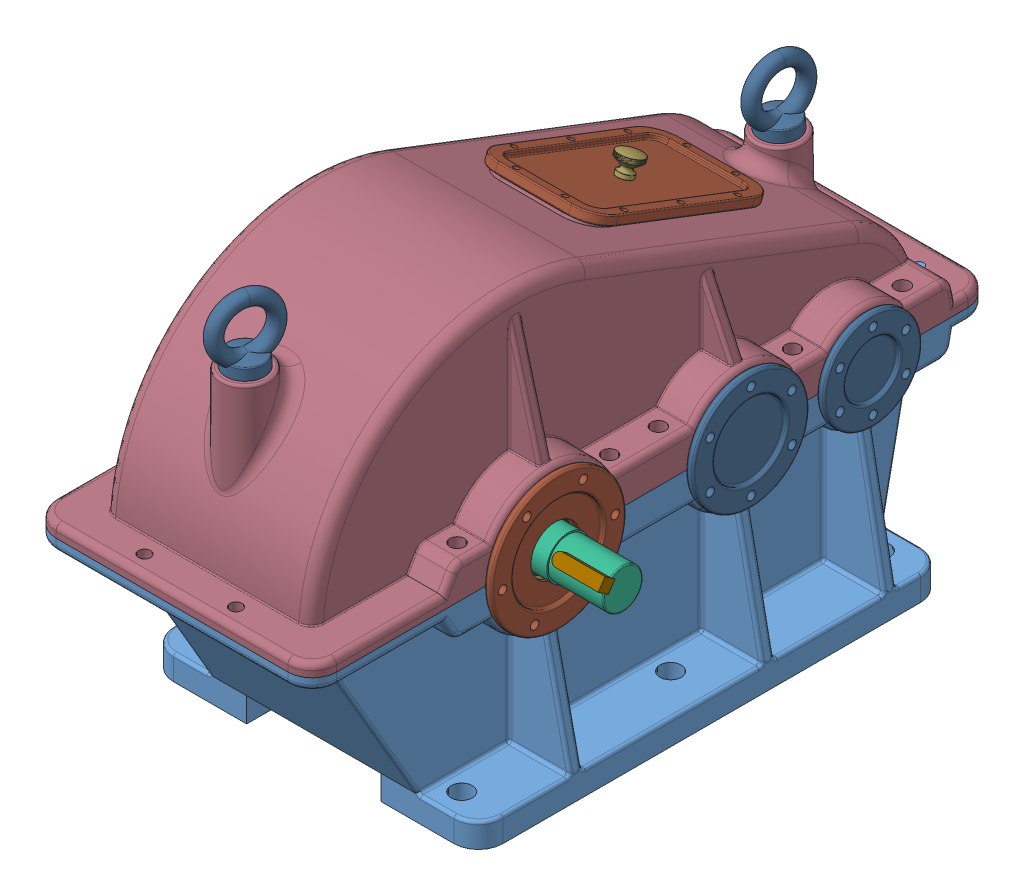
SolidWorks assembly Helical Gearbox Assembly, configuration Default. Lengths in mm.
Overall size (677.13 747.69 1115).
43 component instances, 31 part files, 90 mates.
Components (placement in the parent):
- 01. Shell-1: 01. Shell [Default] at (272.181 704.8513 957.0031) size (540.65 360 1115)
- Oil Plug Seal^Helical Gearbox Assembly-1: Oil Plug Seal^Helical Gearbox Assembly [Default] at (272.181 704.8513 487.0031) x (-1 0 0) z (0 0 -1) size (40 40 3) (virtual)
- 14. Oil Probe-1: 14. Oil Probe [Default] at (272.181 440.499 572.0097) x (-1 0 0) z (0 -0.660132 -0.75115) size (24 180 24)
- 15. Oil Removal Nut-1: 15. Oil Removal Nut [Default] at (272.181 424.8513 484.0031) x (1 0 0) z (0 1 0) size (30 28.09 30)
- 04. Gear 84-1: 04. Gear 84 [ISO - Spur gear 6M 84T 20PA 125FW ---S84A75H50L90.0N] at (159.681 704.8513 1122.0031) x (1 0 0) z (0 -0.823359 0.567521) size (125 515.77 515.77)
- 06. Shaft Slow-1: 06. Shaft Slow [Default] at (83.181 704.8513 1122.0031) x (0 -0.823359 0.567521) z (-1 0 0) size (110 110 536.13)
- 10. Ring Distance 85x137.5-1: 10. Ring Distance 85x137.5 [Default] at (284.681 704.8513 1122.0031) x (-1 0 0) z (0 -0.99103 -0.133637) size (137.5 110 110)
- 11.3 Key 115x16 D18-1: 11.3 Key 115x16 D18 [Default] at (222.181 725.8496 1152.4674) x (1 0 0) z (0 -0.823359 0.567521) size (115 16 18)
- 11.4 Key 160x20 D20-1: 11.4 Key 160x20 D20 [Default] at (619.181 717.6205 1140.5287) x (1 0 0) z (0 -0.823359 0.567521) size (80 20 20)
- 16. Cover Plate Bearing-1: 16. Cover Plate Bearing [CV-80] at (36.181 704.8513 1122.0031) size (55 220 220)
- 17. Cover Plate Bearing (Hole)-1: 17. Cover Plate Bearing (Hole) [CV-80] at (508.181 704.8513 1122.0031) x (-1 0 0) z (0 -0.429637 -0.903002) size (55 220 220)
- 19. Cuff 70x92-1: 19. Cuff 70x92 [Default] at (502.181 704.8513 1122.0031) size (10 92 92)
  - Part2^19. Cuff 70x92-1: Part2^19. Cuff 70x92 [Default] at origin size (10 92 92) (virtual)
  - Part3^19. Cuff 70x92-1: Part3^19. Cuff 70x92 [Default] at origin size (6.5 91 91) (virtual)
  - Part4^19. Cuff 70x92-1: Part4^19. Cuff 70x92 [Default] at origin size (3.73 83.55 83.54) (virtual)
- angular contact ball bearing_68_iso-1: angular contact ball bearing_68_iso [ISO 15 ABB - 0375 - 12,SI,NC,12_68] at (440.681 704.8513 1122.0031) x (-1 0 0) z (0 -0.924225 -0.381849) size (37 160 160)
- angular contact ball bearing_68_iso-2: angular contact ball bearing_68_iso [ISO 15 ABB - 0375 - 12,SI,NC,12_68] at (103.681 704.8513 1122.0031) size (37 160 160)
- 05. Shaft Speed Gear 28-1: 05. Shaft Speed Gear 28 [ISO - Spur gear 4M 28T 20PA 85FW ---S28A75H50L0.8N] at (398.681 704.8513 607.0031) x (-1 0 0) z (0 -0.40996 -0.912103) size (507 119.49 119.49)
- 11.5 Key 100x12 D12-1: 11.5 Key 100x12 D12 [Default] at (-57.819 715.3405 602.2886) x (-1 0 0) z (0 -0.40996 -0.912103) size (50 12 12)
- 16. Cover Plate Bearing-2: 16. Cover Plate Bearing [CV-55] at (508.181 704.8513 607.0031) x (-1 0 0) z (0 -0.866025 -0.5) size (67 160 160)
- 17. Cover Plate Bearing (Hole)-2: 17. Cover Plate Bearing (Hole) [CV-55] at (36.181 704.8513 607.0031) x (1 0 0) z (0 0.866025 0.5) size (67 160 160)
- 18. Cuff 40x60-1: 18. Cuff 40x60 [Default] at (42.181 704.8513 607.0031) x (-1 0 0) z (0 0 -1) size (10 60 60)
  - Part1^18. Cuff 40x60-1: Part1^18. Cuff 40x60 [Default] at origin size (6.5 59 59) (virtual)
  - Part2^18. Cuff 40x60-1: Part2^18. Cuff 40x60 [Default] at origin size (10 60 60) (virtual)
  - Part3^18. Cuff 40x60-1: Part3^18. Cuff 40x60 [Default] at origin size (3.75 53.63 53.66) (virtual)
- angular contact ball bearing_68_iso-3: angular contact ball bearing_68_iso [ISO 15 ABB - 0345 - 10,SI,NC,10_68] at (434.681 704.8513 607.0031) x (-1 0 0) z (0 -0.924225 -0.381849) size (25 100 100)
- angular contact ball bearing_68_iso-4: angular contact ball bearing_68_iso [ISO 15 ABB - 0345 - 10,SI,NC,10_68] at (109.681 704.8513 607.0031) x (-1 0 0) z (0 -0.924225 -0.381849) size (25 100 100)
- 03. Gear 72-1: 03. Gear 72 [ISO - Spur gear 4M 72T 20PA 80FW ---S72A75H50L80.0N] at (316.681 704.8513 807.0031) x (1 0 0) z (0 0.837056 -0.547117) size (80 295.82 295.82)
- 07. Shaft Middle-1: 07. Shaft Middle [Default] at (455.181 704.8513 807.0031) x (0 0.837056 -0.547117) z (-1 0 0) size (100 100 365.5)
- 08. Ring Distance 60x25.5-1: 08. Ring Distance 60x25.5 [Default] at (396.681 704.8513 807.0031) x (0 -0.984693 -0.174299) z (1 0 0) size (90 90 25.5)
- 09. Ring Distance 60x35-1: 09. Ring Distance 60x35 [Default] at (157.681 704.8513 807.0031) x (1 0 0) z (0 0.963027 -0.269404) size (35 90 90)
- 11.1 Key 70x12 D16-1: 11.1 Key 70x12 D16 [Default] at (356.681 686.2494 778.5432) x (1 0 0) z (0 0.837056 -0.547117) size (70 12 16)
- 16. Cover Plate Bearing-3: 16. Cover Plate Bearing [CV-65] at (36.181 704.8513 807.0031) size (61 190 190)
- angular contact ball bearing_68_iso-5: angular contact ball bearing_68_iso [ISO 15 ABB - 0360 - 10,SI,NC,10_68] at (437.681 704.8513 807.0031) x (-1 0 0) z (0 -0.924225 -0.381849) size (31 130 130)
- angular contact ball bearing_68_iso-6: angular contact ball bearing_68_iso [ISO 15 ABB - 0360 - 10,SI,NC,10_68] at (106.681 704.8513 807.0031) x (-1 0 0) z (0 -0.924225 -0.381849) size (31 130 130)
- 11.2 Key 125x12 D12-1: 11.2 Key 125x12 D12 [Default] at (222.681 690.3527 784.8211) x (1 0 0) z (0 0.837056 -0.547117) size (125 12 12)
- 16. Cover Plate Bearing-4: 16. Cover Plate Bearing [CV-65] at (508.181 704.8513 807.0031) x (-1 0 0) z (0 -0.866025 -0.5) size (61 190 190)
- Gear 21-2: Gear 21 [ISO - Spur gear 6M 21T 20PA 130FW ---S21A75H50L65.0N] at (157.681 704.8513 807.0031) x (1 0 0) z (0 0.647031 -0.762463) size (130 137.45 137.82)
- 02. Eye Bolt-1: 02. Eye Bolt [Default] at (272.181 984.8513 1394.5031) x (0.963727 0 0.266888) z (-0.266888 0 0.963727) size (63 164 109.27)
- 12.Door Cover Plate-1: 12.Door Cover Plate [Default] at (272.181 935.8311 775.5954) x (1 0 0) z (0 0.359223 0.933252) size (200 25.72 320)
- 13. Blunking Plug-1: 13. Blunking Plug [Default] at (272.181 927.8985 778.6488) x (-0.612037 -0.284084 -0.738043) z (0.790829 -0.219858 -0.571185) size (40.1 50 40.08)
- 20. Cover-1: 20. Cover [Default] at (272.181 704.8513 957.0031) size (462.08 335 1115)
- 02. Eye Bolt-2: 02. Eye Bolt [Default] at (272.181 884.8513 519.5031) x (0.996756 0 0.080487) z (-0.080487 0 0.996756) size (63 164 109.27)
Mates (geometry in assembly coordinates):
- Concentric1: concentric: cylinder of 01. Shell-1 through (42.181 704.8513 1122.0031) axis (1 0 0) radius 80; cylinder of 17. Cover Plate Bearing (Hole)-1 through (502.181 704.8513 1122.0031) axis (-1 0 0) radius 80
- Coincident1: coincident: plane of 01. Shell-1 through (502.181 684.8513 957.0031) normal (1 0 0); plane of 17. Cover Plate Bearing (Hole)-1 through (502.181 804.1815 1074.7431) normal (-1 0 0)
- Concentric2: concentric: cylinder of 01. Shell-1 through (502.181 704.8513 1122.0031) axis (-1 0 0) radius 80; cylinder of 16. Cover Plate Bearing-1 through (42.181 704.8513 1122.0031) axis (1 0 0) radius 80
- Coincident2: coincident: plane of 01. Shell-1 through (42.181 684.8513 957.0031) normal (-1 0 0); plane of 16. Cover Plate Bearing-1 through (42.181 814.8513 1122.0031) normal (1 0 0)
- Concentric3: concentric: cylinder of assembly; cylinder of assembly; cylinder of 01. Shell-1 through (502.181 704.8513 1122.0031) axis (-1 0 0) radius 80; cylinder of 06. Shaft Slow-1 through (83.181 704.8513 1122.0031) axis (-1 0 0) radius 42.5; plane of ?; plane of ?
- Coincident3: coincident: line of assembly; plane of assembly; line of 06. Shaft Slow-1 through (549.181 714.1673 1153.1393) axis (1 0 0); plane of ?; plane of ?; plane of 11.4 Key 160x20 D20-1 through (549.181 720.7374 1162.6711) normal (0 -0.823359 0.567521)
- Coincident4: coincident: plane of 06. Shaft Slow-1 through (619.181 717.6205 1140.5287) normal (0 0.567521 0.823359); line of 11.4 Key 160x20 D20-1 through (619.181 725.8541 1134.8535) axis (0 -0.823359 0.567521)
- Coincident5: coincident: circle of 06. Shaft Slow-1; circle of 11.4 Key 160x20 D20-1
- Concentric4: concentric: cylinder of assembly; cylinder of assembly; cylinder of 06. Shaft Slow-1 through (270.681 731.5248 1160.701) axis (0 -0.567521 -0.823359) radius 9; plane of ?; plane of ?; cylinder of 11.3 Key 115x16 D18-1 through (270.681 734.9299 1165.6412) axis (0 -0.567521 -0.823359) radius 9
- Coincident6: coincident: line of 06. Shaft Slow-1 through (173.681 722.4635 1163.4134) axis (1 0 0); plane of 11.3 Key 115x16 D18-1 through (173.681 727.5197 1170.7489) normal (0 -0.823359 0.567521)
- Coincident7: coincident: plane of 06. Shaft Slow-1 through (270.681 725.8496 1152.4674) normal (0 0.567521 0.823359); line of 11.3 Key 115x16 D18-1 through (173.681 718.4394 1157.5751) axis (1 0 0)
- Concentric5: concentric: cylinder of assembly; cylinder of assembly; cylinder of 06. Shaft Slow-1 through (83.181 704.8513 1122.0031) axis (-1 0 0) radius 42.5; plane of ?; plane of ?; plane of ?; cylinder of 10. Ring Distance 85x137.5-1 through (379.571 704.8513 1122.0031) axis (1 0 0) radius 42.5
- Concentric6: concentric: cylinder of assembly; cylinder of assembly; cylinder of 04. Gear 84-1 through (284.6811 704.8513 1122.0031) axis (-1 0 0) radius 45; cylinder of 06. Shaft Slow-1 through (83.181 704.8513 1122.0031) axis (-1 0 0) radius 42.5; plane of ?; plane of ?; plane of ?
- Coincident8: coincident: plane of 04. Gear 84-1 through (159.681 742.3402 1160.5335) normal (0 -0.823359 0.567521); line of 11.3 Key 115x16 D18-1 through (270.681 742.3402 1160.5335) axis (-1 0 0)
- Coincident9: coincident: plane of 04. Gear 84-1 through (284.681 704.8513 1122.0031) normal (1 0 0); plane of 10. Ring Distance 85x137.5-1 through (284.681 710.5309 1079.8843) normal (-1 0 0)
- Coincident10: coincident: plane of 17. Cover Plate Bearing (Hole)-1 through (502.181 768.0615 1091.9286) normal (-1 0 0); plane of 19. Cuff 70x92-1/Part2^19. Cuff 70x92-1 through (502.181 750.8513 1122.0031) normal (1 0 0)
- Concentric8: concentric: cylinder of 17. Cover Plate Bearing (Hole)-1 through (502.181 704.8513 1122.0031) axis (-1 0 0) radius 80; cylinder of 19. Cuff 70x92-1/Part2^19. Cuff 70x92-1 through (454.9144 704.8513 1122.0031) axis (-1 0 0) radius 46
- Concentric9: concentric: cylinder of assembly; cylinder of assembly; cylinder of 06. Shaft Slow-1 through (83.181 704.8513 1122.0031) axis (-1 0 0) radius 35; plane of ?; plane of ?; plane of ?; cylinder of angular contact ball bearing_68_iso-1 through (461.3185 704.8513 1122.0031) axis (-1 0 0) radius 37.5
- Concentric10: concentric: cylinder of 16. Cover Plate Bearing-1 through (42.181 704.8513 1122.0031) axis (1 0 0) radius 70; cylinder of angular contact ball bearing_68_iso-2 through (83.0435 704.8513 1122.0031) axis (1 0 0) radius 37.5
- Coincident11: coincident: plane of 01. Shell-1 through (122.181 704.8513 957.0031) normal (1 0 0); plane of angular contact ball bearing_68_iso-2 through (122.181 782.7513 1122.0031) normal (1 0 0)
- Coincident12: coincident: plane of 06. Shaft Slow-1 through (122.181 728.971 1156.9959) normal (-1 0 0); plane of angular contact ball bearing_68_iso-2 through (122.181 744.4513 1122.0031) normal (1 0 0)
- Coincident13: coincident: plane of 01. Shell-1 through (422.181 704.8513 957.0031) normal (-1 0 0); plane of angular contact ball bearing_68_iso-1 through (422.181 734.5974 1050.006) normal (-1 0 0)
- Coincident14: coincident: plane of 04. Gear 84-1 through (284.681 704.8513 1122.0031) normal (1 0 0); plane of 06. Shaft Slow-1 through (284.681 728.971 1156.9959) normal (1 0 0)
- Concentric11: concentric: cylinder of 01. Shell-1 through (502.181 704.8513 607.0031) axis (-1 0 0) radius 50; cylinder of 05. Shaft Speed Gear 28-1 through (88.8045 704.8513 607.0031) axis (-1 0 0) radius 27.5
- Concentric12: concentric: cylinder of 05. Shaft Speed Gear 28-1 through (88.8045 704.8513 607.0031) axis (-1 0 0) radius 27.5; cylinder of 17. Cover Plate Bearing (Hole)-2 through (42.181 704.8513 607.0031) axis (1 0 0) radius 50
- Coincident15: coincident: plane of 01. Shell-1 through (42.181 684.8513 957.0031) normal (-1 0 0); plane of 17. Cover Plate Bearing (Hole)-2 through (42.181 744.8513 537.7211) normal (1 0 0)
- Concentric13: concentric: axis of 01. Shell-1 through (72.181 673.6013 661.1297) axis (-1 0 0); cylinder of 17. Cover Plate Bearing (Hole)-2 through (97.181 673.6013 661.1297) axis (-1 0 0) radius 7
- Concentric14: concentric: cylinder of 05. Shaft Speed Gear 28-1 through (88.8045 704.8513 607.0031) axis (-1 0 0) radius 20; cylinder of 18. Cuff 40x60-1/Part2^18. Cuff 40x60-1 through (75.4112 704.8513 607.0031) axis (1 0 0) radius 30
- Coincident16: coincident: plane of 17. Cover Plate Bearing (Hole)-2 through (42.181 724.8513 572.3621) normal (1 0 0); plane of 18. Cuff 40x60-1/Part2^18. Cuff 40x60-1 through (42.181 734.8513 607.0031) normal (-1 0 0)
- Concentric15: concentric: cylinder of 01. Shell-1 through (42.181 704.8513 607.0031) axis (1 0 0) radius 50; cylinder of 16. Cover Plate Bearing-2 through (502.181 704.8513 607.0031) axis (-1 0 0) radius 50
- Coincident17: coincident: plane of 01. Shell-1 through (502.181 684.8513 957.0031) normal (1 0 0); plane of 16. Cover Plate Bearing-2 through (502.181 744.8513 537.7211) normal (-1 0 0)
- Concentric16: concentric: line of 01. Shell-1 through (472.181 673.6013 661.1297) axis (1 0 0); cylinder of 16. Cover Plate Bearing-2 through (447.181 673.6013 661.1297) axis (1 0 0) radius 7
- Concentric17: concentric: cylinder of 05. Shaft Speed Gear 28-1 through (88.8045 704.8513 607.0031) axis (-1 0 0) radius 22.5; cylinder of angular contact ball bearing_68_iso-3 through (455.3185 704.8513 607.0031) axis (-1 0 0) radius 22.5
- Concentric18: concentric: cylinder of 05. Shaft Speed Gear 28-1 through (88.8045 704.8513 607.0031) axis (-1 0 0) radius 27.5; cylinder of angular contact ball bearing_68_iso-4 through (130.3185 704.8513 607.0031) axis (-1 0 0) radius 22.5
- Coincident18: coincident: plane of 01. Shell-1 through (122.181 704.8513 957.0031) normal (1 0 0); plane of angular contact ball bearing_68_iso-4 through (122.181 721.8341 565.8982) normal (1 0 0)
- Coincident19: coincident: plane of 01. Shell-1 through (422.181 704.8513 957.0031) normal (-1 0 0); plane of angular contact ball bearing_68_iso-3 through (422.181 723.371 562.1782) normal (-1 0 0)
- Coincident20: coincident: plane of 05. Shaft Speed Gear 28-1 through (422.181 729.9342 595.7292) normal (1 0 0); plane of angular contact ball bearing_68_iso-3 through (422.181 714.0157 584.8217) normal (-1 0 0)
- Coincident21: coincident: plane of 05. Shaft Speed Gear 28-1 through (-13.819 715.3405 602.2886) normal (0 0.912103 -0.40996); plane of 11.5 Key 100x12 D12-1 through (-13.819 715.3405 602.2886) normal (0 -0.912103 0.40996)
- Concentric19: concentric: cylinder of 05. Shaft Speed Gear 28-1 through (-13.819 759.345 582.51) axis (0 -0.912103 0.40996) radius 6; cylinder of 11.5 Key 100x12 D12-1 through (-13.819 726.2858 597.3691) axis (0 -0.912103 0.40996) radius 6
- Coincident22: coincident: line of 05. Shaft Speed Gear 28-1 through (-13.819 722.3054 605.7363) axis (-1 0 0); plane of 11.5 Key 100x12 D12-1 through (-13.819 728.7455 602.8417) normal (0 0.40996 0.912103)
- Concentric20: concentric: cylinder of 01. Shell-1 through (502.181 704.8513 807.0031) axis (-1 0 0) radius 65; cylinder of 16. Cover Plate Bearing-3 through (42.181 704.8513 807.0031) axis (1 0 0) radius 65
- Coincident23: coincident: plane of 01. Shell-1 through (42.181 684.8513 957.0031) normal (-1 0 0); plane of 16. Cover Plate Bearing-3 through (42.181 799.8513 807.0031) normal (1 0 0)
- Concentric21: concentric: line of 01. Shell-1 through (72.181 666.1013 874.1201) axis (-1 0 0); cylinder of 16. Cover Plate Bearing-3 through (91.181 666.1013 874.1201) axis (-1 0 0) radius 7
- Concentric22: concentric: cylinder of 07. Shaft Middle-1 through (455.181 704.8513 807.0031) axis (-1 0 0) radius 40; cylinder of 16. Cover Plate Bearing-3 through (42.181 704.8513 807.0031) axis (1 0 0) radius 65
- Concentric24: concentric: cylinder of 07. Shaft Middle-1 through (455.181 704.8513 807.0031) axis (-1 0 0) radius 30; cylinder of 08. Ring Distance 60x25.5-1 through (427.4437 704.8513 807.0031) axis (1 0 0) radius 30
- Concentric25: concentric: cylinder of 07. Shaft Middle-1 through (455.181 704.8513 807.0031) axis (-1 0 0) radius 30; cylinder of 09. Ring Distance 60x35-1 through (100.5577 704.8513 807.0031) axis (-1 0 0) radius 30
- Coincident24: coincident: circle of 07. Shaft Middle-1; plane of 09. Ring Distance 60x35-1 through (157.681 696.7692 778.1123) normal (1 0 0)
- Coincident25: coincident: plane of 07. Shaft Middle-1 through (396.681 682.9667 773.5209) normal (1 0 0); circle of 08. Ring Distance 60x25.5-1
- Coincident26: coincident: plane of 07. Shaft Middle-1 through (383.681 686.2494 778.5432) normal (0 -0.547117 -0.837056); plane of 11.1 Key 70x12 D16-1 through (329.681 686.2494 778.5432) normal (0 0.547117 0.837056)
- Coincident27: coincident: line of 07. Shaft Middle-1 through (329.681 690.1053 769.8204) axis (1 0 0); plane of 11.1 Key 70x12 D16-1 through (329.681 686.3804 764.1216) normal (0 0.837056 -0.547117)
- Coincident28: coincident: cylinder of 07. Shaft Middle-1 through (329.681 680.7782 770.1727) axis (0 0.547117 0.837056) radius 8; circle of 11.1 Key 70x12 D16-1
- Concentric26: concentric: cylinder of 07. Shaft Middle-1 through (455.181 704.8513 807.0031) axis (-1 0 0) radius 30; cylinder of angular contact ball bearing_68_iso-5 through (458.3185 704.8513 807.0031) axis (-1 0 0) radius 30
- Concentric27: concentric: cylinder of 07. Shaft Middle-1 through (455.181 704.8513 807.0031) axis (-1 0 0) radius 32.5; cylinder of angular contact ball bearing_68_iso-6 through (127.3185 704.8513 807.0031) axis (-1 0 0) radius 30
- Coincident29: coincident: plane of 01. Shell-1 through (122.181 704.8513 957.0031) normal (1 0 0); plane of angular contact ball bearing_68_iso-6 through (122.181 726.989 753.4212) normal (1 0 0)
- Coincident30: coincident: plane of 01. Shell-1 through (422.181 704.8513 957.0031) normal (-1 0 0); plane of angular contact ball bearing_68_iso-5 through (422.181 728.8696 748.8694) normal (-1 0 0)
- Coincident31: coincident: plane of 08. Ring Distance 60x25.5-1 through (422.181 711.1261 771.5542) normal (1 0 0); plane of angular contact ball bearing_68_iso-5 through (422.181 717.1087 777.3355) normal (-1 0 0)
- Concentric28: concentric: cylinder of 03. Gear 72-1 through (396.6811 704.8513 807.0031) axis (-1 0 0) radius 40; cylinder of 07. Shaft Middle-1 through (455.181 704.8513 807.0031) axis (-1 0 0) radius 40
- Coincident32: coincident: plane of 03. Gear 72-1 through (316.681 692.9458 774.1663) normal (0 -0.837056 0.547117); plane of 11.1 Key 70x12 D16-1 through (329.681 686.3804 764.1216) normal (0 0.837056 -0.547117)
- Coincident33: coincident: plane of 03. Gear 72-1 through (396.681 704.8513 807.0031) normal (1 0 0); plane of 08. Ring Distance 60x25.5-1 through (396.681 710.0803 777.4623) normal (-1 0 0)
- Coincident34: coincident: plane of 07. Shaft Middle-1 through (279.181 690.3527 784.8211) normal (0 -0.547117 -0.837056); plane of 11.2 Key 125x12 D12-1 through (166.181 690.3527 784.8211) normal (0 0.547117 0.837056)
- Coincident35: coincident: plane of 07. Shaft Middle-1 through (279.181 689.9039 773.1679) normal (0 -0.837056 0.547117); plane of 11.2 Key 125x12 D12-1 through (166.181 688.8097 771.4938) normal (0 0.837056 -0.547117)
- Concentric30: concentric: cylinder of 07. Shaft Middle-1 through (279.181 684.8816 776.4506) axis (0 0.547117 0.837056) radius 6; cylinder of 11.2 Key 125x12 D12-1 through (279.181 683.7873 774.7765) axis (0 0.547117 0.837056) radius 6
- Concentric31: concentric: cylinder of 01. Shell-1 through (42.181 704.8513 807.0031) axis (1 0 0) radius 65; cylinder of 16. Cover Plate Bearing-4 through (502.181 704.8513 807.0031) axis (-1 0 0) radius 65
- Coincident36: coincident: plane of 01. Shell-1 through (502.181 684.8513 957.0031) normal (1 0 0); plane of 16. Cover Plate Bearing-4 through (502.181 752.3513 724.7307) normal (-1 0 0)
- Concentric32: concentric: cylinder of 01. Shell-1 through (472.181 666.1013 874.1201) axis (1 0 0) radius 7; cylinder of 16. Cover Plate Bearing-4 through (453.181 666.1013 874.1201) axis (1 0 0) radius 7
- Concentric33: concentric: cylinder of 07. Shaft Middle-1 through (455.181 704.8513 807.0031) axis (-1 0 0) radius 32.5; cylinder of Gear 21-2 through (287.6811 704.8513 807.0031) axis (-1 0 0) radius 32.5
- Coincident37: coincident: plane of 09. Ring Distance 60x35-1 through (157.681 696.7692 778.1123) normal (1 0 0); plane of Gear 21-2 through (157.681 704.8513 807.0031) normal (-1 0 0)
- Coincident38: coincident: plane of 11.2 Key 125x12 D12-1 through (166.181 678.765 778.0592) normal (0 -0.837056 0.547117); plane of Gear 21-2 through (287.681 699.829 810.2858) normal (0 0.837056 -0.547117)
- InPlace1: in place: plane of ? through (272.181 424.8513 487.0031) normal (0 0 -1); plane of ? through (0 0 487.0031) normal (0 0 -1); moOrthogonalPlaneRef_w of ? through (272.181 424.8513 487.0031) normal (0 0 -1); plane of ? through (0 0 487.0031) normal (0 1 0); plane of ? through (272.181 424.8513 487.0031) normal (0 0 -1); plane of ? through (0 0 487.0031) normal (-1 0 0); plane of ? through (272.181 424.8513 487.0031) normal (0 0 -1); unknown of Oil Plug Seal^Helical Gearbox Assembly-1
- Coincident39: coincident: plane of 01. Shell-1; plane of ?
- Coincident40: coincident: plane of 01. Shell-1 through (272.181 704.8513 487.0031) normal (0 1 0); plane of Part2^Helical Gearbox Assembly-1 through (272.181 704.8513 487.0031) normal (0 1 0)
- Coincident41: coincident: plane of 01. Shell-1 through (272.181 704.8513 487.0031) normal (1 0 0); plane of Part2^Helical Gearbox Assembly-1 through (272.181 704.8513 487.0031) normal (-1 0 0)
- Concentric34: concentric: cylinder of 01. Shell-1 through (272.181 424.8513 567.0031) axis (0 0 -1) radius 25; cylinder of 15. Oil Removal Nut-1 through (272.181 424.8513 480.0031) axis (0 0 1) radius 15
- Concentric35: concentric: line of 01. Shell-1 through (272.181 482.4719 535.1227) axis (0 0.75115 -0.660132); cylinder of 14. Oil Probe-1 through (272.181 440.499 572.0097) axis (0 -0.75115 0.660132) radius 3.5
- Coincident42: coincident: plane of Oil Plug Seal^Helical Gearbox Assembly-1 through (272.181 704.8513 484.0031) normal (0 0 -1); circle of 15. Oil Removal Nut-1
- Coincident43: coincident: plane of 01. Shell-1 through (292.181 571.2566 483.7221) normal (0 0.75115 -0.660132); circle of 14. Oil Probe-1
- Coincident44: coincident: plane of 01. Shell-1 through (272.181 704.8513 957.0031) normal (0 1 0); line of 20. Cover-1 through (82.181 704.8513 1514.5031) axis (1 0 0)
- Coincident45: coincident: plane of 01. Shell-1 through (502.181 684.8513 957.0031) normal (1 0 0); plane of 20. Cover-1 through (502.181 684.8513 957.0031) normal (1 0 0)
- Coincident46: coincident: plane of 01. Shell-1 through (272.181 684.8513 1514.5031) normal (0 0 1); plane of 20. Cover-1 through (272.181 684.8513 1514.5031) normal (0 0 1)
- Coincident47: coincident: plane of 12.Door Cover Plate-1 through (272.181 935.8311 775.5954) normal (0 -0.933252 0.359223); plane of 20. Cover-1 through (202.181 892.7243 663.6052) normal (0 0.933252 -0.359223)
- Width1: width: plane of 20. Cover-1 through (442.181 704.8513 1122.0031) normal (1 0 0); plane of 12.Door Cover Plate-1 through (102.181 704.8513 1122.0031) normal (-1 0 0); plane of 20. Cover-1 through (172.181 949.8299 770.207) normal (-1 0 0); plane of 12.Door Cover Plate-1 through (372.181 949.8299 770.207) normal (1 0 0)
- Width2: width: plane of 12.Door Cover Plate-1 through (272.181 1007.3056 919.5273) normal (0 0.359223 0.933252); plane of 20. Cover-1 through (272.181 892.3542 620.8868) normal (0 -0.359223 -0.933252); plane of 12.Door Cover Plate-1 through (322.181 878.3554 626.2751) normal (0 -0.359223 -0.933252); plane of 20. Cover-1 through (202.181 993.3068 924.9156) normal (0 0.359223 0.933252)
- Concentric36: concentric: circle of 12.Door Cover Plate-1; cylinder of 13. Blunking Plug-1 through (272.181 927.8985 778.6488) axis (0 -0.933252 0.359223) radius 12.5
- Coincident48: coincident: plane of 12.Door Cover Plate-1 through (332.181 985.9373 884.8914) normal (0 0.933252 -0.359223); circle of 13. Blunking Plug-1
- Concentric37: concentric: cone of 02. Eye Bolt-1 through (272.181 984.8513 1394.5031) axis (0 1 0); cylinder of 20. Cover-1 through (272.181 973.8513 1394.5031) axis (0 1 0) radius 19
- Coincident49: coincident: circle of 02. Eye Bolt-1; plane of 20. Cover-1 through (272.181 984.8513 1394.5031) normal (0 1 0)
- Concentric38: concentric: cylinder of 20. Cover-1 through (272.181 364.8493 519.5031) axis (0 1 0) radius 40; cylinder of 02. Eye Bolt-2 through (272.181 884.8513 519.5031) axis (0 1 0) radius 50.6145
- Coincident50: coincident: plane of 20. Cover-1 through (272.181 884.8513 519.5031) normal (0 1 0); circle of 02. Eye Bolt-2
- GearMate1: gear = 21 : 84 mm: circle of 04. Gear 84-1; circle of Gear 21-2
- GearMate2: gear = 28 : 72 mm: circle of 03. Gear 72-1; circle of 05. Shaft Speed Gear 28-1
